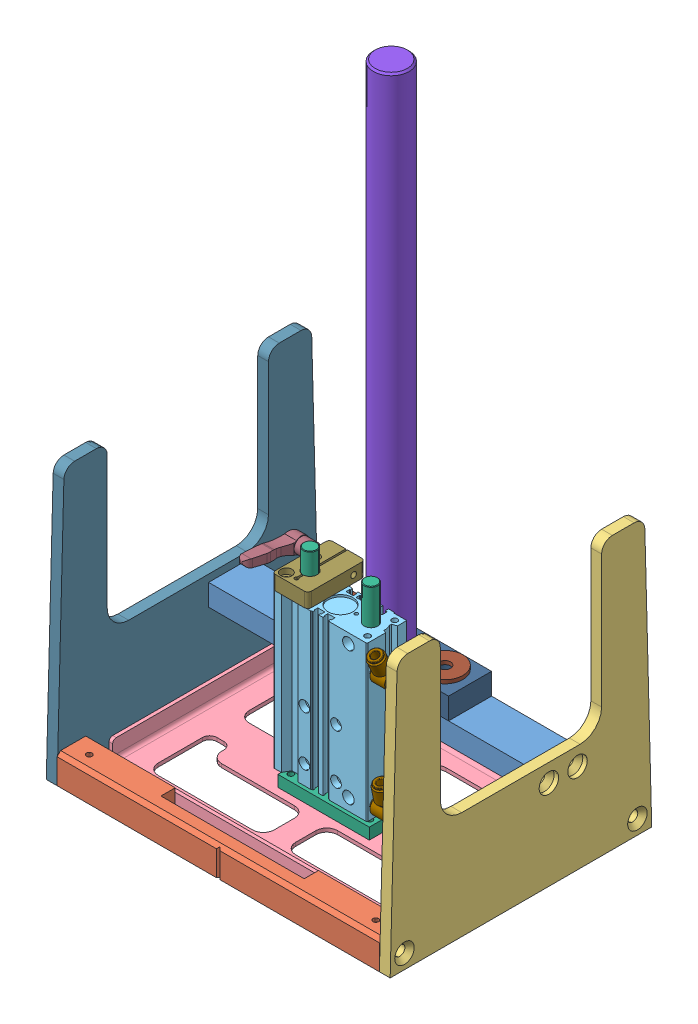
SolidWorks assembly MANDREL ASSEMBLY, configuration Default. Lengths in mm.
Overall size (304.8 552.45 231.84).
18 component instances, 14 part files, 40 mates.
Components (placement in the parent):
- MANDREL CENTER MOUNT BAR-1: MANDREL CENTER MOUNT BAR [Default] at origin size (285.75 19.05 38.1)
- MANDREL SPREADER-1: MANDREL SPREADER [Default] at (0 -66.675 140.6779) size (285.75 25.4 25.4)
- MANDREL SPREADER-2: MANDREL SPREADER [Default] at (0 -66.675 -65.7606) x (-1 0 0) z (0 0 -1) size (285.75 25.4 25.4)
- MANDREL SIDE PLATE 2-1: MANDREL SIDE PLATE 2 [5086-21-107] at (142.875 -31.75 37.4587) x (0 1 0) z (1 0 0) size (241.3 231.84 9.53)
- PUSHER PLATE-1: PUSHER PLATE [Default] at (0 -76.2 38.2334) x (-1 0 0) z (0 0 -1) size (275.34 19.05 173.84)
- CYLINDER ASSEMBLY-1: CYLINDER ASSEMBLY [MGPM20N-100] at (0 8.3 44.9875) x (1 0 0) z (0 -1 0) size (83 36 184.5)
  - 5321-31 SMC MGPM20N-100_MGPTube-1: 5321-31 SMC MGPM20N-100_MGPTube [20M] at origin size (83 36 137)
  - 5321-31 SMC MGPM20N-100_MGPRod-1: 5321-31 SMC MGPM20N-100_MGPRod [20M] at (0 0 -52.5) size (81 30 184.5)
- CYLINDER PUSHER MOUNT-1: CYLINDER PUSHER MOUNT [Default] at (0 -9.525 26.9875) x (0 0 -1) z (1 0 0) size (50.8 50.8 76.2)
- MANDREL STEM-1: MANDREL STEM [Default] at (0 244.475 0) x (1 0 0) z (0 -1 0) size (31.75 31.75 457.2)
- ELBOW-1: ELBOW [Default] at (51.0375 52.3 55.4875) x (0 -0.90635 -0.422527) z (0 -0.422527 0.90635) size (31 36.1 14.2)
- ELBOW-2: ELBOW [Default] at (51.0375 -49.7 55.4875) x (0 -0.979591 -0.201) z (0 -0.201 0.979591) size (31 36.1 14.2)
- MANDREL MNT-1: MANDREL MNT [Default] at (0 19.05 0) x (0 0 -1) z (-1 0 0) size (38.1 19.05 139.7)
- WASHER ECCENT-1: WASHER ECCENT [Default] at (47.625 30.1625 0) x (-0.379258 0 0.925291) z (0.925291 0 0.379258) size (31.75 3.17 31.75)
- WASHER ECCENT-2: WASHER ECCENT [Default] at (-47.625 30.1625 0) x (-0.379258 0 0.925291) z (0.925291 0 0.379258) size (31.75 3.17 31.75)
- EJECT CYLINDER CLAMP PLATE-1: EJECT CYLINDER CLAMP PLATE [Default] at (-26.475 83.15 37.9375) x (-1 0 0) z (0 0 -1) size (31.75 12.7 50.8)
- ORANGE HANDLE-1: ORANGE HANDLE [Default] at (-42.35 83.15 22.7625) x (0 0 1) z (0 -1 0) size (46.51 30.96 14.49)
- MANDREL SIDE PLATE-2: MANDREL SIDE PLATE [5086-21-107] at (-142.875 -31.75 37.4587) x (0 1 0) z (1 0 0) size (241.3 231.84 9.53)
Mates (geometry in assembly coordinates):
- Coincident1: coincident: plane of MANDREL CENTER MOUNT BAR-1 through (142.875 9.525 19.05) normal (1 0 0); plane of MANDREL SIDE PLATE 2-1 through (142.875 -79.375 -78.4606) normal (-1 0 0)
- Concentric1: concentric: cylinder of MANDREL CENTER MOUNT BAR-1 through (142.875 0 12.7) axis (1 0 0) radius 3.4; cylinder of MANDREL SIDE PLATE 2-1 through (152.4 0 12.7) axis (1 0 0) radius 4.5
- Concentric2: concentric: cylinder of MANDREL CENTER MOUNT BAR-1 through (142.875 0 -12.7) axis (1 0 0) radius 3.4; cylinder of MANDREL SIDE PLATE 2-1 through (152.4 0 -12.7) axis (1 0 0) radius 4.5
- Coincident2: coincident: plane of MANDREL SIDE PLATE 2-1 through (142.875 -79.375 -78.4606) normal (-1 0 0); plane of MANDREL SPREADER-1 through (142.875 -79.375 153.3779) normal (1 0 0)
- Coincident22: coincident: plane of MANDREL SPREADER-2 through (142.875 -79.375 -78.4606) normal (1 0 0); plane of MANDREL SIDE PLATE 2-1 through (142.875 -79.375 -78.4606) normal (-1 0 0)
- Coincident23: coincident: plane of MANDREL SIDE PLATE 2-1 through (152.4 -79.375 153.3779) normal (0 -1 0); plane of MANDREL SPREADER-2 through (-142.875 -79.375 -78.4606) normal (0 -1 0)
- Coincident72: coincident: plane of MANDREL CENTER MOUNT BAR-1 through (142.875 -9.525 19.05) normal (0 -1 0); plane of CYLINDER PUSHER MOUNT-1 through (38.1 -9.525 26.9875) normal (0 1 0)
- Coincident75: coincident: plane of PUSHER PLATE-1 through (131.318 -76.2 -42.3354) normal (0 1 0); plane of CYLINDER ASSEMBLY-1/5321-31 SMC MGPM20N-100_MGPRod-1 through (-40.5 -76.2 29.9875) normal (0 -1 0)
- Coincident77: coincident: plane of MANDREL SPREADER-2 through (-142.875 -79.375 -78.4606) normal (0 -1 0); plane of PUSHER PLATE-1 through (131.318 -79.375 -42.3354) normal (0 -1 0)
- Coincident78: coincident: plane of CYLINDER ASSEMBLY-1/5321-31 SMC MGPM20N-100_MGPTube-1 through (0 8.3 44.9875) normal (1 0 0); plane of CYLINDER PUSHER MOUNT-1 through (0 -9.525 26.9875) normal (1 0 0)
- Coincident79: coincident: plane of CYLINDER ASSEMBLY-1/5321-31 SMC MGPM20N-100_MGPTube-1 through (-41.5 -150.671 26.9875) normal (0 0 -1); plane of CYLINDER PUSHER MOUNT-1 through (38.1 -9.525 26.9875) normal (0 0 1)
- Coincident80: coincident: plane of ELBOW-1 through (36.7375 54.6304 61.8882) normal (-1 0 0); plane of ELBOW-2 through (36.7375 -45.9498 61.1739) normal (-1 0 0)
- Distance1: distance = 4.7625 mm: plane of CYLINDER ASSEMBLY-1/5321-31 SMC MGPM20N-100_MGPTube-1 through (41.5 -150.671 62.9875) normal (1 0 0); plane of ELBOW-2 through (36.7375 -45.9498 61.1739) normal (-1 0 0)
- Concentric65: concentric: circle of CYLINDER ASSEMBLY-1/5321-31 SMC MGPM20N-100_MGPTube-1; cylinder of ELBOW-1 through (56.7375 52.3 55.4875) axis (-1 0 0) radius 7.1
- Concentric66: concentric: circle of CYLINDER ASSEMBLY-1/5321-31 SMC MGPM20N-100_MGPTube-1; circle of ELBOW-2
- Coincident87: coincident: plane of MANDREL CENTER MOUNT BAR-1 through (0 0 0) normal (0 0 1); plane of MANDREL STEM-1 through (0 244.475 0) normal (0 0 1)
- Distance2: distance = 6.35 mm: plane of MANDREL CENTER MOUNT BAR-1 through (142.875 9.525 19.05) normal (0 1 0); plane of MANDREL STEM-1 through (0 15.875 0) normal (0 -1 0)
- Coincident89: coincident: plane of MANDREL CENTER MOUNT BAR-1 through (0 0 0) normal (1 0 0); plane of MANDREL STEM-1 through (0 244.475 0) normal (1 0 0)
- Coincident90: coincident: plane of MANDREL CENTER MOUNT BAR-1 through (142.875 9.525 19.05) normal (0 1 0); plane of MANDREL MNT-1 through (-69.85 9.525 19.05) normal (0 -1 0)
- Coincident91: coincident: plane of MANDREL CENTER MOUNT BAR-1 through (0 0 0) normal (0 0 1); plane of MANDREL MNT-1 through (0 19.05 0) normal (0 0 -1)
- Coincident92: coincident: plane of MANDREL CENTER MOUNT BAR-1 through (0 0 0) normal (1 0 0); plane of MANDREL MNT-1 through (0 19.05 0) normal (-1 0 0)
- Coincident93: coincident: plane of WASHER ECCENT-1 through (47.625 28.575 0) normal (0 -1 0); plane of WASHER ECCENT-2 through (-47.625 28.575 0) normal (0 -1 0)
- Coincident94: coincident: plane of MANDREL MNT-1 through (-69.85 28.575 19.05) normal (0 1 0); plane of WASHER ECCENT-1 through (47.625 28.575 0) normal (0 -1 0)
- Concentric67: concentric: cylinder of MANDREL MNT-1 through (47.625 28.576 0) axis (0 -1 0) radius 9.525; cylinder of WASHER ECCENT-1 through (47.625 28.575 0) axis (0 1 0) radius 4.9609
- Concentric68: concentric: cylinder of MANDREL MNT-1 through (-47.625 28.576 0) axis (0 -1 0) radius 9.525; cylinder of WASHER ECCENT-2 through (-47.625 28.575 0) axis (0 1 0) radius 4.9609
- Concentric69: concentric: cylinder of MANDREL CENTER MOUNT BAR-1 through (-19.05 -9.525 -12.7) axis (0 -1 0) radius 2.1; cylinder of CYLINDER PUSHER MOUNT-1 through (-19.05 -9.525 -12.7) axis (0 1 0) radius 2.7781
- Concentric70: concentric: cylinder of MANDREL CENTER MOUNT BAR-1 through (19.05 -9.525 12.7) axis (0 -1 0) radius 2.1; cylinder of CYLINDER PUSHER MOUNT-1 through (19.05 -9.525 12.7) axis (0 1 0) radius 2.7781
- Concentric71: concentric: cylinder of CYLINDER ASSEMBLY-1/5321-31 SMC MGPM20N-100_MGPRod-1 through (-27 125.2706 44.9875) axis (0 -1 0) radius 6; cylinder of EJECT CYLINDER CLAMP PLATE-1 through (-27 76.799 44.9875) axis (0 1 0) radius 6
- Concentric72: concentric: cylinder of CYLINDER ASSEMBLY-1/5321-31 SMC MGPM20N-100_MGPTube-1 through (-36 63.8 56.9875) axis (0 1 0) radius 2.5; cylinder of EJECT CYLINDER CLAMP PLATE-1 through (-36 89.5 56.9875) axis (0 1 0) radius 5
- Coincident95: coincident: plane of CYLINDER ASSEMBLY-1/5321-31 SMC MGPM20N-100_MGPTube-1 through (0 76.8 44.9875) normal (0 1 0); plane of EJECT CYLINDER CLAMP PLATE-1 through (-10.6 76.8 12.5375) normal (0 -1 0)
- Coincident96: coincident: plane of EJECT CYLINDER CLAMP PLATE-1 through (-42.35 76.8 12.5375) normal (-1 0 0); plane of ORANGE HANDLE-1 through (-42.35 83.15 27.4625) normal (1 0 0)
- Concentric73: concentric: cylinder of EJECT CYLINDER CLAMP PLATE-1 through (-42.35 83.15 22.7625) axis (-1 0 0) radius 3.3735; cylinder of ORANGE HANDLE-1 through (-42.35 83.15 22.7625) axis (-1 0 0) radius 5
- Parallel1: parallel: plane of EJECT CYLINDER CLAMP PLATE-1 through (-10.6 89.5 12.5375) normal (0 1 0); plane of ORANGE HANDLE-1 through (-42.35 83.15 22.7625) normal (0 -1 0)
- Coincident97: coincident: plane of MANDREL SPREADER-1 through (-142.875 -79.375 153.3779) normal (-1 0 0); plane of MANDREL SIDE PLATE-2 through (-142.875 -79.375 -78.4606) normal (1 0 0)
- Concentric76: concentric: cylinder of MANDREL SPREADER-1 through (-142.875 -66.675 140.6779) axis (-1 0 0) radius 3.4; cylinder of MANDREL SIDE PLATE-2 through (-152.4 -66.675 140.6779) axis (-1 0 0) radius 4.5
- Concentric77: concentric: cylinder of MANDREL SPREADER-2 through (-142.875 -66.675 -65.7606) axis (-1 0 0) radius 3.4; cylinder of MANDREL SIDE PLATE-2 through (-152.4 -66.675 -65.7606) axis (-1 0 0) radius 4.5
- Coincident98: coincident: plane of PUSHER PLATE-1 through (131.318 -76.2 -42.3354) normal (0 1 0); plane of CYLINDER ASSEMBLY-1/5321-31 SMC MGPM20N-100_MGPRod-1 through (-40.5 -76.2 29.9875) normal (0 -1 0)
- Concentric78: concentric: circle of PUSHER PLATE-1; circle of CYLINDER ASSEMBLY-1/5321-31 SMC MGPM20N-100_MGPRod-1
- Concentric79: concentric: circle of PUSHER PLATE-1; cylinder of CYLINDER ASSEMBLY-1/5321-31 SMC MGPM20N-100_MGPRod-1 through (35 108.3 35.9875) axis (0 -1 0) radius 2.5
- Concentric80: concentric: cylinder of MANDREL SPREADER-1 through (142.875 -66.675 140.6779) axis (1 0 0) radius 3.4; cylinder of MANDREL SIDE PLATE 2-1 through (152.4 -66.675 140.6779) axis (1 0 0) radius 4.5
